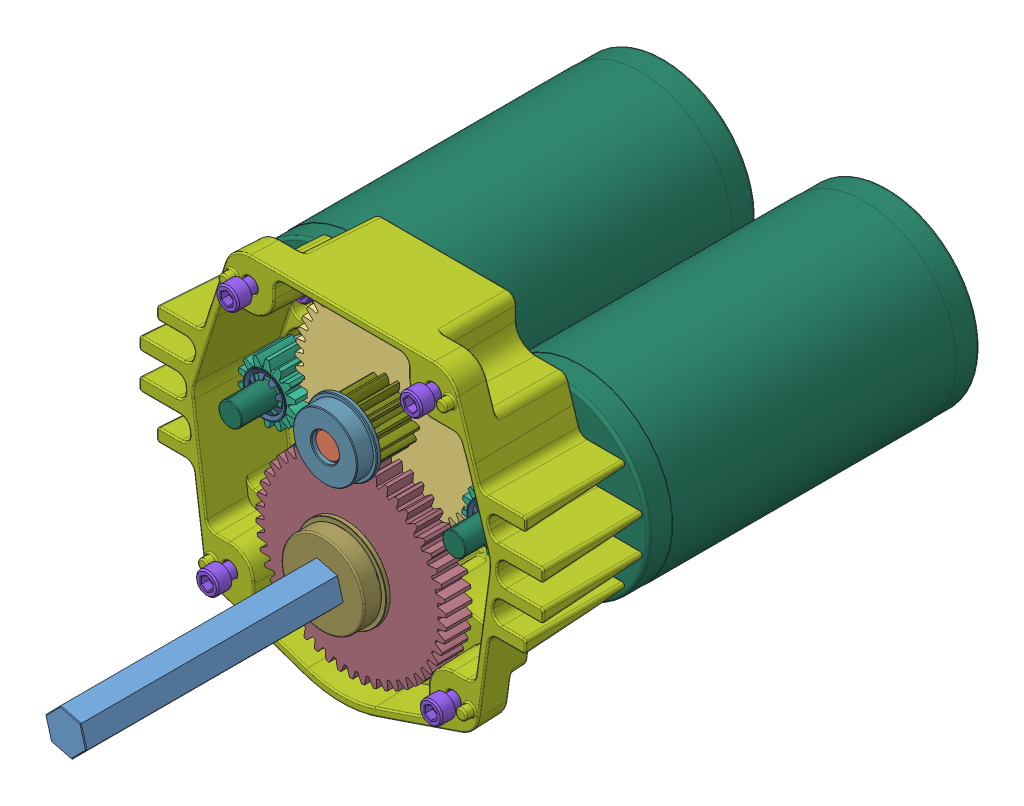
SolidWorks assembly Toughbox Mini L-Base, configuration Default. Lengths in mm.
Overall size (141.56 126.31 250.48).
33 component instances, 16 part files, 67 mates.
Components (placement in the parent):
- TB Output Shaft Hex L-Base 2-1: TB Output Shaft Hex L-Base 2 [Default] at (-85.3818 51.5734 -52.3197) x (-0.270026 0.962853 0) z (0.962853 0.270026 0) size (14.66 142.29 12.7)
- Toughbox d07-1: Toughbox d07 [Default] at (-48.9083 57.3574 -52.3959) x (0.850542 0.525907 0) z (0.525907 -0.850542 0) size (11 38.23 9.52)
- Toughbox d05-1: Toughbox d05 [Default] at (-91.0349 50.9043 -67.5597) x (0.850542 0.525907 0) z (0 0 -1) size (65.97 66.04 10.16)
- 10-32 Nylock Nut-1: 10-32 Nylock Nut [Default] at (-129.8464 -8.0737 -56.3837) x (0.501678 0.865055 0) z (0 0 -1) size (10.18 11.01 7.1)
- 10-32 Nylock Nut-2: 10-32 Nylock Nut [Default] at (-59.2462 80.7349 -56.3837) x (0.999999 -0.001296 0) z (0 0 -1) size (10.18 11.01 7.1)
- 10-32 Nylock Nut-3: 10-32 Nylock Nut [Default] at (-122.7461 80.8172 -56.3837) x (0.500567 0.865698 0) z (0 0 -1) size (10.18 11.01 7.1)
- 10-32 Nylock Nut-4: 10-32 Nylock Nut [Default] at (-52.3764 -8.1741 -56.3837) x (-0.501678 -0.865055 0) z (0 0 -1) size (10.18 11.01 7.1)
- 5-16 washer-1: 5-16 washer [Default] at (-52.3162 38.3079 -77.7705) x (0.38418 -0.923258 0) z (0 0 -1) size (17.53 17.53 1.47)
- 5-16 washer-2: 5-16 washer [Default] at (-52.3162 38.3079 -76.2973) x (0.897267 -0.441488 0) z (0 0 -1) size (17.53 17.53 1.47)
- 5-16 washer-3: 5-16 washer [Default] at (-129.7861 38.4083 -77.7705) x (-0.990116 0.140253 0) z (0 0 1) size (17.53 17.53 1.47)
- 5-16 washer-4: 5-16 washer [Default] at (-129.7861 38.4083 -79.2437) x (-0.681761 0.731575 0) z (0 0 1) size (17.53 17.53 1.47)
- Toughbox d09-1: Toughbox d09 [Default] at (-52.3162 38.3079 -63.5973) x (-0.164234 0.986421 0) z (0 0 -1) size (20.03 20.32 12.7)
- Toughbox d09-2: Toughbox d09 [Default] at (-129.7861 38.4083 -63.5973) x (0.999999 -0.001296 0) z (0 0 -1) size (20.03 20.32 12.7)
- TM Housing-1: TM Housing [Default] at (-91.0876 10.1882 -86.3557) x (0.999999 -0.001296 0) z (0 0 1) size (139.9 118.55 41.54)
- SHCS 10-32 x 0.625-1: SHCS 10-32 x 0.625 [Default] at (-52.2832 63.7078 -74.4685) x (-0.564778 -0.825243 0) z (-0.825243 0.564778 0) size (7.82 20.65 7.82)
- SHCS 10-32 x 0.625-2: SHCS 10-32 x 0.625 [Default] at (-122.7462 80.7273 -42.5915) x (0.507484 -0.861661 0) z (-0.861661 -0.507484 0) size (7.82 20.65 7.82)
- SHCS 10-32 x 0.625-3: SHCS 10-32 x 0.625 [Default] at (-52.2612 -8.1727 -42.5915) x (0.507484 -0.861661 0) z (-0.861661 -0.507484 0) size (7.82 20.65 7.82)
- SHCS 10-32 x 0.625-4: SHCS 10-32 x 0.625 [Default] at (-129.7312 -8.1727 -42.5915) x (0.507484 -0.861661 0) z (-0.861661 -0.507484 0) size (7.82 20.65 7.82)
- SHCS 10-32 x 0.625-5: SHCS 10-32 x 0.625 [Default] at (-59.2462 80.7273 -42.5915) x (0.740711 -0.671824 0) z (-0.671824 -0.740711 0) size (7.82 20.65 7.82)
- SHCS 10-32 x 0.625-6: SHCS 10-32 x 0.625 [Default] at (-52.3491 12.9079 -74.4685) x (-0.564778 -0.825243 0) z (-0.825243 0.564778 0) size (7.82 20.65 7.82)
- SHCS 10-32 x 0.625-7: SHCS 10-32 x 0.625 [Default] at (-129.7532 63.8083 -74.4685) x (-0.966277 -0.257503 0) z (-0.257503 0.966277 0) size (7.82 20.65 7.82)
- SHCS 10-32 x 0.625-8: SHCS 10-32 x 0.625 [Default] at (-129.819 13.0083 -74.4685) x (-0.99652 0.083357 0) z (0.083357 0.99652 0) size (7.82 20.65 7.82)
- R6ZZ Bearing-3: R6ZZ Bearing [Default] at (-91.0349 50.9043 -84.8317) size (22.23 22.23 7.11)
- R6ZZ Bearing-4: R6ZZ Bearing [Default] at (-91.0876 10.1882 -84.8317) x (0.993242 0.116063 0) z (0 0 1) size (22.23 22.23 7.11)
- 8mm spring clip-1: 8mm spring clip [Default] at (-129.7861 38.4083 -63.5973) x (0 0 1) z (-0.993985 0.109516 0) size (1.09 14.83 14.83)
- 8mm spring clip-2: 8mm spring clip [Default] at (-52.3162 38.3079 -63.5973) x (0 0 1) z (-1 0 0) size (1.09 14.83 14.83)
- 500 E-klip-1: 500 E-klip [Default] at (-91.0876 10.1882 -64.2069) size (19.07 20.96 1.27)
- FR8ZZ Hex Bearing-1: FR8ZZ Hex Bearing [Default] at (-91.0876 10.1882 -44.1383) x (-0.968868 0.247577 0) z (0 0 -1) size (31.12 31.12 7.93)
- 50T 20dp 500hex-1: 50T 20dp 500hex [Default] at (-91.0876 10.1882 -62.9369) x (0.968868 -0.247577 0) z (0 0 1) size (65.97 66.04 10.16)
- FR6ZZ Bearing-2: FR6ZZ Bearing [Default] at (-82.1733 44.8624 -52.0657) size (24.69 24.69 7.16)
- CIM Motor SW-1: CIM Motor SW [Default] at (56.9338 2.6062 -105.4057) x (0.001296 0.999999 0) z (0 0 1) size (64.01 64.01 154.93)
- CIM Motor SW-2: CIM Motor SW [Default] at (-239.0361 74.11 -105.4057) x (-0.001296 -0.999999 0) z (0 0 1) size (64.01 64.01 154.93)
- spur gear_ai-1: spur gear_ai [Inch - Spur gear 20DP 14T 14.5PA .568FW ---S14N3.0H2.0L0.25N] at (-91.0349 50.9043 -67.5597) x (0 0 1) z (-0.88072 0.473637 0) size (14.43 19.97 20.32)
Mates (geometry in assembly coordinates):
- Concentric2: concentric aligned: circle of 10-32 Nylock Nut-3; circle of TM Housing-1
- Coincident1: coincident anti-aligned: plane of 10-32 Nylock Nut-3 through (-122.7461 80.8172 -56.3837) normal (0 0 1); plane of TM Housing-1 through (-132.6301 80.83 -56.3837) normal (0 0 -1)
- Parallel1: parallel: plane of 10-32 Nylock Nut-3 through (-125.1247 84.9432 -58.368) normal (-0.499433 0.866352 0); line of TM Housing-1 through (-122.993 86.3757 -60.7105) axis (-0.866352 -0.499433 0)
- Concentric3: concentric anti-aligned: circle of 10-32 Nylock Nut-2; circle of TM Housing-1
- Coincident3: coincident anti-aligned: plane of 10-32 Nylock Nut-2 through (-59.2462 80.7349 -56.3837) normal (0 0 1); plane of TM Housing-1 through (-59.2388 86.4499 -56.3837) normal (0 0 -1)
- Parallel2: parallel: plane of 10-32 Nylock Nut-2 through (-54.4837 80.7287 -58.368) normal (0.999999 -0.001296 0); line of TM Housing-1 through (-54.0512 78.1748 -60.9557) axis (0.001296 0.999999 0)
- Concentric4: concentric anti-aligned: circle of 10-32 Nylock Nut-4; circle of TM Housing-1
- Coincident5: coincident anti-aligned: plane of 10-32 Nylock Nut-4 through (-52.3764 -8.1741 -56.3837) normal (0 0 1); plane of TM Housing-1 through (-62.2604 -8.1613 -56.3837) normal (0 0 -1)
- Parallel3: parallel: plane of 10-32 Nylock Nut-4 through (-49.9872 -4.0543 -58.368) normal (0.501678 0.865055 0); line of TM Housing-1 through (-47.5543 -4.9678 -60.9557) axis (-0.865055 0.501678 0)
- Concentric5: concentric aligned: circle of 10-32 Nylock Nut-1; circle of TM Housing-1
- Coincident9: coincident anti-aligned: plane of 10-32 Nylock Nut-1 through (-129.8464 -8.0737 -56.3837) normal (0 0 1); plane of TM Housing-1 through (-139.7304 -8.0609 -56.3837) normal (0 0 -1)
- Parallel4: parallel: plane of 10-32 Nylock Nut-1 through (-132.2356 -12.1935 -58.368) normal (-0.501678 -0.865055 0); line of TM Housing-1 through (-130.235 -13.8511 -60.9557) axis (-0.865055 0.501678 0)
- Concentric6: concentric aligned: cylinder of TM Housing-1 through (-129.7532 63.8083 -50.5417) axis (0 0 1) radius 2.5527; circle of SHCS 10-32 x 0.625-7
- Coincident11: coincident anti-aligned: plane of TM Housing-1 through (-59.2462 80.7349 -79.2437) normal (0 0 1); plane of SHCS 10-32 x 0.625-7 through (-129.7532 63.8083 -79.2437) normal (0 0 -1)
- Concentric7: concentric anti-aligned: cylinder of TM Housing-1 through (-52.2832 63.7078 -50.5417) axis (0 0 1) radius 2.5527; circle of SHCS 10-32 x 0.625-1
- Coincident12: coincident anti-aligned: plane of TM Housing-1 through (-59.2462 80.7349 -79.2437) normal (0 0 1); plane of SHCS 10-32 x 0.625-1 through (-52.2832 63.7078 -79.2437) normal (0 0 -1)
- Concentric8: concentric aligned: cylinder of TM Housing-1 through (-52.3491 12.9079 -50.5417) axis (0 0 1) radius 2.5527; cylinder of SHCS 10-32 x 0.625-6 through (-52.3491 12.9079 -95.1187) axis (0 0 1) radius 2.3876
- Coincident13: coincident anti-aligned: plane of TM Housing-1 through (-59.2462 80.7349 -79.2437) normal (0 0 1); plane of SHCS 10-32 x 0.625-6 through (-52.3491 12.9079 -79.2437) normal (0 0 -1)
- Concentric9: concentric aligned: cylinder of TM Housing-1 through (-129.819 13.0083 -50.5417) axis (0 0 1) radius 2.5527; cylinder of SHCS 10-32 x 0.625-8 through (-129.819 13.0083 -95.1187) axis (0 0 1) radius 2.3876
- Coincident14: coincident anti-aligned: plane of TM Housing-1 through (-59.2462 80.7349 -79.2437) normal (0 0 1); plane of SHCS 10-32 x 0.625-8 through (-129.819 13.0083 -79.2437) normal (0 0 -1)
- Concentric12: concentric aligned: cylinder of 5-16 washer-3 through (-129.7861 38.4083 -76.2973) axis (0 0 -1) radius 8.763; cylinder of 5-16 washer-4 through (-129.7861 38.4083 -77.7705) axis (0 0 -1) radius 8.763
- Concentric13: concentric anti-aligned: circle of 5-16 washer-4; cylinder of TM Housing-1 through (-129.7861 38.4083 -50.5417) axis (0 0 1) radius 10.414
- Coincident17: coincident anti-aligned: plane of 5-16 washer-4 through (-129.7861 38.4083 -79.2437) normal (0 0 -1); plane of TM Housing-1 through (-59.2462 80.7349 -79.2437) normal (0 0 1)
- Coincident18: coincident anti-aligned: plane of 5-16 washer-3 through (-129.7861 38.4083 -77.7705) normal (0 0 -1); plane of 5-16 washer-4 through (-129.7861 38.4083 -77.7705) normal (0 0 1)
- Concentric14: concentric anti-aligned: circle of 5-16 washer-3; circle of Toughbox d09-2
- Coincident19: coincident anti-aligned: plane of 5-16 washer-3 through (-129.7861 38.4083 -76.2973) normal (0 0 1); plane of Toughbox d09-2 through (-129.7861 38.4083 -76.2973) normal (0 0 -1)
- Coincident21: coincident aligned: circle of 5-16 washer-1; circle of 5-16 washer-2
- Concentric16: concentric aligned: cylinder of 5-16 washer-1 through (-52.3162 38.3079 -79.2437) axis (0 0 1) radius 4.3942; cylinder of TM Housing-1 through (-52.3162 38.3079 -50.5417) axis (0 0 1) radius 10.414
- Coincident22: coincident anti-aligned: plane of 5-16 washer-1 through (-52.3162 38.3079 -79.2437) normal (0 0 -1); plane of TM Housing-1 through (-59.2462 80.7349 -79.2437) normal (0 0 1)
- Coincident23: coincident aligned: plane of 5-16 washer-2 through (-52.3162 38.3079 -76.2973) normal (0 0 1); circle of Toughbox d09-1
- Concentric17: concentric aligned: circle of 5-16 washer-2; cylinder of Toughbox d09-1 through (-52.3162 38.3079 -76.2973) axis (0 0 1) radius 4
- Parallel5: parallel anti-aligned: plane of Toughbox d07-1 through (-86.1916 48.2997 -77.9229) normal (0.999545 0.030178 0); plane of Toughbox d05-1 through (-86.1916 48.2997 -67.5597) normal (-0.999545 -0.030178 0)
- Concentric20: concentric anti-aligned: circle of Toughbox d07-1; circle of Toughbox d05-1
- Coincident37: coincident aligned: plane of SHCS 10-32 x 0.625-4 through (-129.7312 -8.1727 -47.3667) normal (0 0 -1); plane of SHCS 10-32 x 0.625-5 through (-59.2462 80.7273 -47.3667) normal (0 0 -1)
- Coincident39: coincident aligned: plane of SHCS 10-32 x 0.625-2 through (-122.7462 80.7273 -47.3667) normal (0 0 -1); plane of SHCS 10-32 x 0.625-5 through (-59.2462 80.7273 -47.3667) normal (0 0 -1)
- Coincident40: coincident aligned: plane of SHCS 10-32 x 0.625-2 through (-122.7462 80.7273 -47.3667) normal (0 0 -1); plane of SHCS 10-32 x 0.625-3 through (-52.2612 -8.1727 -47.3667) normal (0 0 -1)
- Concentric34: concentric anti-aligned: cylinder of Toughbox d07-1 through (-91.0349 50.9043 -84.2729) axis (0 0 1) radius 4.7498; cylinder of R6ZZ Bearing-3 through (-91.0349 50.9043 -77.7197) axis (0 0 -1) radius 11.1125
- Coincident46: coincident anti-aligned: plane of Toughbox d07-1 through (-90.8689 45.4076 -77.7197) normal (0 0 -1); plane of R6ZZ Bearing-3 through (-91.0349 50.9043 -77.7197) normal (0 0 1)
- Concentric35: concentric anti-aligned: cylinder of TB Output Shaft Hex L-Base 2-1 through (-91.0876 10.1882 -84.8317) axis (0 0 1) radius 4.7498; cylinder of R6ZZ Bearing-4 through (-91.0876 10.1882 -77.7197) axis (0 0 -1) radius 11.1125
- Coincident48: coincident anti-aligned: plane of TB Output Shaft Hex L-Base 2-1 through (-78.8594 13.6175 -77.7197) normal (0 0 -1); plane of R6ZZ Bearing-4 through (-91.0876 10.1882 -77.7197) normal (0 0 1)
- Coincident49: coincident anti-aligned: plane of Toughbox d09-2 through (-129.7861 38.4083 -63.5973) normal (0 0 1); circle of 8mm spring clip-1
- Concentric36: concentric aligned: circle of Toughbox d09-2; circle of 8mm spring clip-1
- Coincident50: coincident anti-aligned: plane of Toughbox d09-1 through (-52.3162 38.3079 -63.5973) normal (0 0 1); circle of 8mm spring clip-2
- Concentric37: concentric aligned: circle of Toughbox d09-1; circle of 8mm spring clip-2
- Concentric46: concentric anti-aligned: cylinder of TB Output Shaft Hex L-Base 2-1 through (-91.0876 10.1882 -77.7197) axis (0 0 1) radius 5.588; cylinder of 500 E-klip-1 through (-91.0876 10.1882 -62.9369) axis (0 0 -1) radius 5.1562
- Coincident59: coincident anti-aligned: plane of TB Output Shaft Hex L-Base 2-1 through (-92.5966 15.5686 -62.9369) normal (0 0 -1); plane of 500 E-klip-1 through (-91.0876 10.1882 -62.9369) normal (0 0 1)
- Concentric48: concentric anti-aligned: cylinder of TM Housing-1 through (-91.0876 10.1882 -50.5417) axis (0 0 1) radius 5.08; cylinder of R6ZZ Bearing-4 through (-91.0876 10.1882 -77.7197) axis (0 0 -1) radius 11.1125
- Coincident60: coincident anti-aligned: plane of TM Housing-1 through (-91.0876 10.1882 -84.8317) normal (0 0 1); plane of R6ZZ Bearing-4 through (-91.0876 10.1882 -84.8317) normal (0 0 -1)
- Concentric49: concentric aligned: cylinder of TB Output Shaft Hex L-Base 2-1 through (-91.0876 10.1882 -97.5317) axis (0 0 1) radius 3.1623; cylinder of FR8ZZ Hex Bearing-1 through (-91.0876 10.1882 -52.0657) axis (0 0 1) radius 14.2875
- Coincident61: coincident anti-aligned: plane of TB Output Shaft Hex L-Base 2-1 through (-85.9635 15.4328 -77.7197) normal (0.247577 0.968868 0); plane of FR8ZZ Hex Bearing-1 through (-85.9635 15.4328 -52.0657) normal (-0.247577 -0.968868 0)
- Coincident69: coincident anti-aligned: plane of Toughbox d05-1 through (-91.0349 50.9043 -77.7197) normal (0 0 -1); plane of R6ZZ Bearing-3 through (-91.0349 50.9043 -77.7197) normal (0 0 1)
- Coincident70: coincident anti-aligned: plane of R6ZZ Bearing-3 through (-91.0349 50.9043 -84.8317) normal (0 0 -1); plane of TM Housing-1 through (-91.0349 50.9043 -84.8317) normal (0 0 1)
- Coincident72: coincident anti-aligned: plane of 500 E-klip-1 through (-91.0876 10.1882 -62.9369) normal (0 0 1); plane of 50T 20dp 500hex-1 through (-91.0876 10.1882 -62.9369) normal (0 0 -1)
- Parallel6: parallel aligned: plane of TB Output Shaft Hex L-Base 2-1 through (-93.0676 17.2481 -77.7197) normal (-0.715276 0.698842 0); plane of 50T 20dp 500hex-1 through (-83.9836 8.3728 -62.9369) normal (-0.715276 0.698842 0)
- Concentric51: concentric aligned: cylinder of FR8ZZ Hex Bearing-1 through (-91.0876 10.1882 -52.0657) axis (0 0 1) radius 14.2875; cone of 50T 20dp 500hex-1 through (-91.0876 10.1882 -53.0944) axis (0 0 1)
- Concentric52: concentric anti-aligned: cylinder of Toughbox d07-1 through (-91.0349 50.9043 -46.0459) axis (0 0 -1) radius 4.7498; cylinder of FR6ZZ Bearing-2 through (-91.0349 50.9043 -44.9029) axis (0 0 1) radius 11.1125
- Coincident73: coincident aligned: plane of TM Housing-1 through (-91.0876 10.1882 -50.5417) normal (0 0 1); plane of FR6ZZ Bearing-2 through (-91.0349 50.9043 -50.5417) normal (0 0 1)
- Concentric54: concentric aligned: cylinder of TM Housing-1 through (-91.0349 50.9043 -84.8317) axis (0 0 -1) radius 11.1061; cylinder of R6ZZ Bearing-3 through (-91.0349 50.9043 -77.7197) axis (0 0 -1) radius 11.1125
- Concentric55: concentric anti-aligned: cylinder of Toughbox d09-1 through (-52.3162 38.3079 -76.2973) axis (0 0 1) radius 4; cylinder of CIM Motor SW-1 through (-52.3162 38.3079 -50.7917) axis (0 0 -1) radius 4
- Concentric56: concentric aligned: cylinder of SHCS 10-32 x 0.625-1 through (-52.2832 63.7078 -95.1187) axis (0 0 1) radius 2.3876; cylinder of CIM Motor SW-1 through (-52.2832 63.7078 -86.3557) axis (0 0 1) radius 2.0193
- Coincident77: coincident anti-aligned: plane of TM Housing-1 through (-91.0876 10.1882 -86.3557) normal (0 0 -1); plane of CIM Motor SW-1 through (-52.3162 38.3079 -86.3557) normal (0 0 1)
- Concentric57: concentric anti-aligned: cylinder of Toughbox d09-2 through (-129.7861 38.4083 -76.2973) axis (0 0 1) radius 4; cylinder of CIM Motor SW-2 through (-129.7861 38.4083 -50.7917) axis (0 0 -1) radius 4
- Concentric58: concentric aligned: cylinder of SHCS 10-32 x 0.625-7 through (-129.7532 63.8083 -95.1187) axis (0 0 1) radius 2.3876; cylinder of CIM Motor SW-2 through (-129.7532 63.8083 -86.3557) axis (0 0 1) radius 2.0193
- Coincident79: coincident anti-aligned: plane of TM Housing-1 through (-91.0876 10.1882 -86.3557) normal (0 0 -1); plane of CIM Motor SW-2 through (-129.7861 38.4083 -86.3557) normal (0 0 1)
- Coincident80: coincident anti-aligned: plane of Toughbox d05-1 through (-91.0349 50.9043 -67.5597) normal (0 0 1); plane of spur gear_ai-1 through (-91.0349 50.9043 -67.5597) normal (0 0 -1)
- GearMate1: gear = 30.4601 : 7.112 mm: cylinder of spur gear_ai-1 through (-94.4806 43.0173 -53.1325) axis (0 0 -1) radius 3.556; cylinder of 50T 20dp 500hex-1 through (-81.1222 38.7297 -62.9369) axis (0 0 1) radius 15.2301
- GearMate3: gear = 17.2539 : 30.4601 mm: cylinder of Toughbox d05-1 through (-66.0857 33.8319 -67.5597) axis (0 0 -1) radius 15.2301; cylinder of Toughbox d09-1 through (-62.3412 37.3784 -63.5973) axis (0 0 -1) radius 8.627
